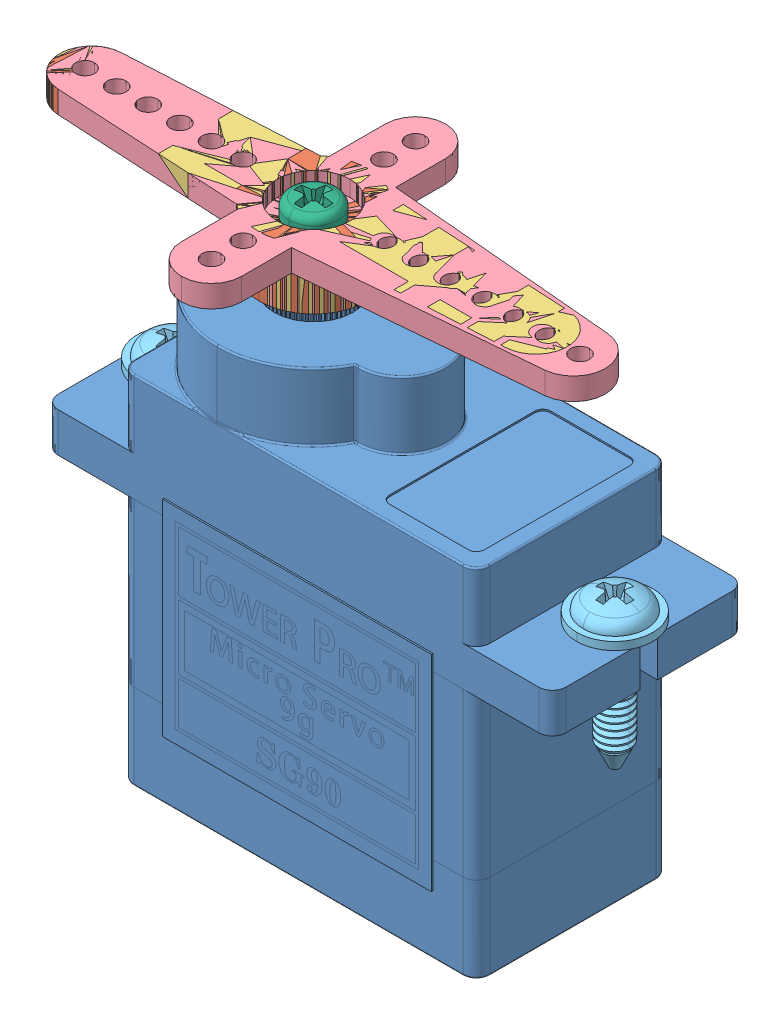
SolidWorks assembly SG90 - Micro Servo 9g - Tower Pro.STEP, configuration Default. Lengths in mm.
Overall size (37.5 32.03 16.7).
7 component instances, 6 part files, 0 mates.
Components (placement in the parent):
- SG90 - Micro Servo 9g - Tower Pro.1_Pe_a.STEP-1: SG90 - Micro Servo 9g - Tower Pro.1_Pe_a.STEP [Default] at (6.6733 16.8178 27.7832) size (32.1 29.95 12.4)
- SG90 - Micro Servo 9g - Tower Pro.2_Pe_a^SG90 - Micro Servo 9g - Tower Pro.STEP-1: SG90 - Micro Servo 9g - Tower Pro.2_Pe_a^SG90 - Micro Servo 9g - Tower Pro.STEP [Default] at (1.5233 37.9178 27.7832) size (19.5 3.8 6.9) (virtual)
- SG90 - Micro Servo 9g - Tower Pro.3_Pe_a^SG90 - Micro Servo 9g - Tower Pro.STEP-1: SG90 - Micro Servo 9g - Tower Pro.3_Pe_a^SG90 - Micro Servo 9g - Tower Pro.STEP [Default] at (1.5233 37.9178 27.7832) size (32.1 3.8 6.9) (virtual)
- SG90 - Micro Servo 9g - Tower Pro.4_Pe_a^SG90 - Micro Servo 9g - Tower Pro.STEP-1: SG90 - Micro Servo 9g - Tower Pro.4_Pe_a^SG90 - Micro Servo 9g - Tower Pro.STEP [Default] at (1.5233 37.9178 27.7832) size (34.5 3.8 16.7) (virtual)
- SG90 - Micro Servo 9g - Tower Pro.5_BS EN ISO 7045 - M2 x 8 - Z - 8S^SG90 - Micro Servo 9g - Tower Pro.STEP-1: SG90 - Micro Servo 9g - Tower Pro.5_BS EN ISO 7045 - M2 x 8 - Z - 8S^SG90 - Micro Servo 9g - Tower Pro.STEP [Default] at (20.5733 26.0678 27.7832) x (0 -1 0) z (0 0 1) size (9.57 4.8 4.8) (virtual)
- SG90 - Micro Servo 9g - Tower Pro.5_BS EN ISO 7045 - M2 x 8 - Z - 8S^SG90 - Micro Servo 9g - Tower Pro.STEP-2: SG90 - Micro Servo 9g - Tower Pro.5_BS EN ISO 7045 - M2 x 8 - Z - 8S^SG90 - Micro Servo 9g - Tower Pro.STEP [Default] at (-7.2267 26.0678 27.7832) x (0 -1 0) z (0 0 -1) size (9.57 4.8 4.8) (virtual)
- SG90 - Micro Servo 9g - Tower Pro.6_BS EN ISO 7045 - M2 x 4 - Z - 4S^SG90 - Micro Servo 9g - Tower Pro.STEP-1: SG90 - Micro Servo 9g - Tower Pro.6_BS EN ISO 7045 - M2 x 4 - Z - 4S^SG90 - Micro Servo 9g - Tower Pro.STEP [Default] at (1.5233 38.2178 27.7832) x (0 -1 0) z (0 0 1) size (5.28 3.1 3.1) (virtual)
